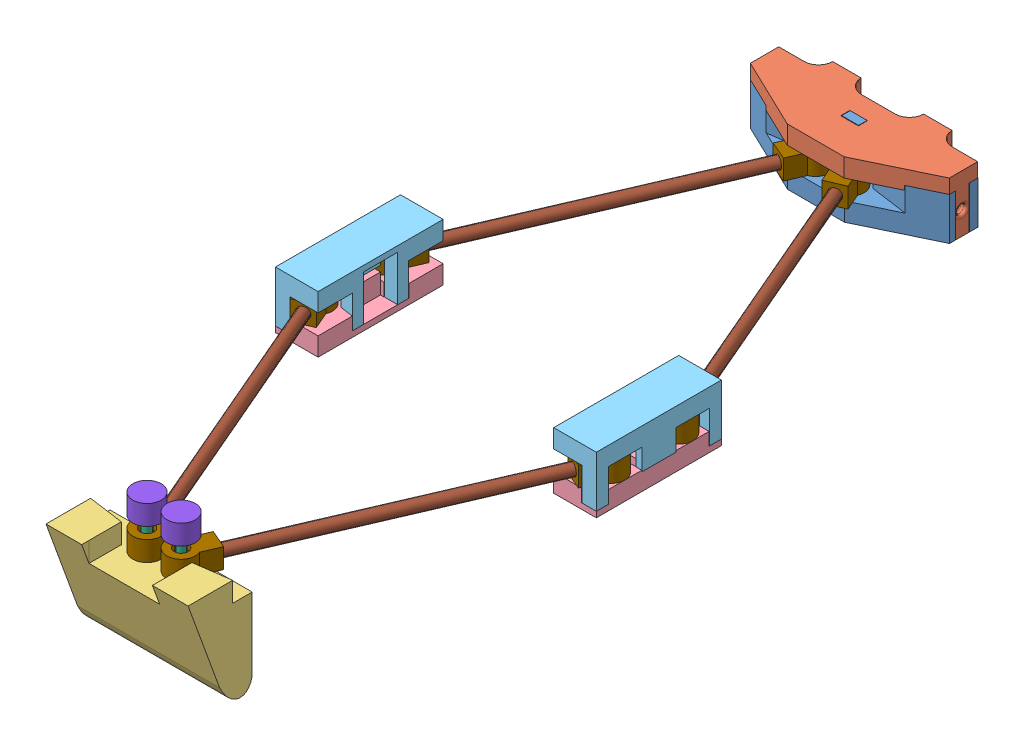
SolidWorks assembly rear_assembly, configuration Default. Lengths in mm.
Overall size (116.04 48.6 272.82).
37 component instances, 11 part files, 88 mates.
Components (placement in the parent):
- Hips3-1: Hips3 [Default] at (9.7538 31.3061 68.3502) size (70 26 22)
- Hips3top-1: Hips3top [Default] at (29.7538 51.3061 68.4502) x (-1 0 0) z (0 0 1) size (70.01 25 27)
- Foot3-1: Foot3 [Default] at (-5.2462 37.8061 311.7254) x (0 0 -1) z (0 -1 0) size (22.55 50 37.6)
- KneeJointBottom-1: KneeJointBottom [Default] at (-21.6962 31.3061 158.0878) x (0 0 1) z (-1 0 0) size (44 9 15)
- KneeJointTop-1: KneeJointTop [Default] at (-21.6962 51.3061 202.0878) x (0 0 -1) z (-1 0 0) size (44 18 15)
- RodFootJoint-1: RodFootJoint [Default] at (13.7538 17.8061 297.7254) size (3 36 3)
- RodFootJoint-2: RodFootJoint [Default] at (25.7538 17.8061 297.7254) size (3 36 3)
- RodHipKneeJoint-1: RodHipKneeJoint [Default] at (-31.6962 33.3061 192.0878) size (3 16 3)
- RodHipKneeJoint-2: RodHipKneeJoint [Default] at (-31.6962 33.3061 168.0878) x (0.999944 0 -0.010618) z (0.010618 0 0.999944) size (3 16 3)
- RodHipKneeJoint-3: RodHipKneeJoint [Default] at (25.7538 33.3061 62.4502) size (3 16 3)
- RodHipKneeJoint-4: RodHipKneeJoint [Default] at (13.7538 33.3061 62.4502) size (3 16 3)
- FootEndConnector-3: FootEndConnector [Default] at (25.7538 48.8061 297.7254) x (0.269607 0 -0.96297) z (0 1 0) size (10 10 9)
- FootEndConnector-4: FootEndConnector [Default] at (13.7538 48.8061 297.7254) x (-0.093538 0 -0.995616) z (0 1 0) size (10 10 9)
- KneeJointTop-2: KneeJointTop [Default] at (61.2038 51.3061 158.0878) x (0 0 1) z (1 0 0) size (44 18 15)
- KneeJointBottom-2: KneeJointBottom [Default] at (61.2038 31.3061 202.0878) x (0 0 -1) z (1 0 0) size (44 9 15)
- RodHipKneeJoint-5: RodHipKneeJoint [Default] at (71.2038 33.3061 192.0878) x (0.987949 0 0.154781) z (-0.154781 0 0.987949) size (3 16 3)
- RodHipKneeJoint-6: RodHipKneeJoint [Default] at (71.2038 33.3061 168.0878) x (0.987949 0 0.154781) z (-0.154781 0 0.987949) size (3 16 3)
- LegConnector1-1: LegConnector1 [Default] at (13.7538 44.8061 62.4502) x (-0.918588 0 -0.395217) z (-0.395217 0 0.918588) size (10 7 15)
- bushing-1: bushing [Default] at (13.7538 38.7061 62.4502) x (0.837169 0 0.546944) z (0.546944 0 -0.837169) size (7.5 5 7.5)
- LegConnector1-2: LegConnector1 [Default] at (25.7538 44.8061 62.4502) x (-0.918588 0 0.395217) z (0.395217 0 0.918588) size (10 7 15)
- bushing-2: bushing [Default] at (25.7538 38.7061 62.4502) x (-0.837169 0 -0.546944) z (-0.546944 0 0.837169) size (7.5 5 7.5)
- LegConnector1-4: LegConnector1 [Default] at (-31.6962 44.8061 192.0878) x (-0.918588 0 0.395217) z (0.395217 0 0.918588) size (10 7 15)
- bushing-4: bushing [Default] at (-31.6962 38.7061 192.0878) x (-0.837169 0 -0.546944) z (-0.546944 0 0.837169) size (7.5 5 7.5)
- LegConnector1-5: LegConnector1 [Default] at (-31.6962 44.8061 168.0878) x (0.918588 0 0.395217) z (0.395217 0 -0.918588) size (10 7 15)
- bushing-5: bushing [Default] at (-31.6962 38.7061 168.0878) x (-0.837169 0 -0.546944) z (-0.546944 0 0.837169) size (7.5 5 7.5)
- LegCarbon-1: LegCarbon [Default] at (11.7777 41.3061 293.1324) x (-0.661738 -0.693573 0.284709) z (0.637107 -0.720387 -0.274112) size (4 105 4)
- LegCarbon-2: LegCarbon [Default] at (-29.7201 41.3061 163.4949) x (-0.61253 0.745221 -0.263538) z (-0.684551 -0.666818 -0.294524) size (4 105 4)
- LegConnector1-6: LegConnector1 [Default] at (13.7538 44.8061 297.7254) x (0.918588 0 -0.395217) z (-0.395217 0 -0.918588) size (10 7 15)
- bushing-6: bushing [Default] at (13.7538 38.7061 297.7254) x (-0.429251 0 -0.903185) z (-0.903185 0 0.429251) size (7.5 5 7.5)
- LegConnector1-8: LegConnector1 [Default] at (71.2038 44.8061 168.0878) x (0.918588 0 -0.395217) z (-0.395217 0 -0.918588) size (10 7 15)
- bushing-8: bushing [Default] at (71.2038 38.7061 168.0878) x (-0.429251 0 -0.903185) z (-0.903185 0 0.429251) size (7.5 5 7.5)
- bushing-9: bushing [Default] at (25.7538 38.7061 297.7254) x (-0.429251 0 -0.903185) z (-0.903185 0 0.429251) size (7.5 5 7.5)
- LegConnector1-9: LegConnector1 [Default] at (71.2038 44.8061 192.0878) x (-0.918588 0 -0.395217) z (-0.395217 0 0.918588) size (10 7 15)
- bushing-10: bushing [Default] at (71.2038 38.7061 192.0878) x (-0.429251 0 -0.903185) z (-0.903185 0 0.429251) size (7.5 5 7.5)
- LegConnector1-10: LegConnector1 [Default] at (25.7538 44.8061 297.7254) x (0.918588 0 0.395217) z (0.395217 0 -0.918588) size (10 7 15)
- LegCarbon-3: LegCarbon [Default] at (27.7299 41.3061 67.0432) x (0.650562 -0.705991 -0.279901) z (-0.648515 -0.70822 0.27902) size (4 105 4)
- LegCarbon-4: LegCarbon [Default] at (27.7299 41.3061 293.1324) x (-0.617739 0.740108 -0.265779) z (-0.679854 -0.672488 -0.292504) size (4 105 4)
Mates (geometry in assembly coordinates):
- Coincident1: coincident anti-aligned: plane of Hips3-1 through (-15.2462 29.3061 54.3502) normal (0 0 -1); plane of Hips3top-1 through (-15.2462 31.3061 54.3502) normal (0 0 1)
- Coincident2: coincident aligned: plane of Hips3-1 through (9.7538 31.3061 68.3502) normal (0 -1 0); plane of Hips3top-1 through (29.7538 31.3061 68.4502) normal (0 -1 0)
- Coincident3: coincident aligned: plane of Hips3-1 through (-15.2462 36.3061 56.3502) normal (-1 0 0); plane of Hips3top-1 through (-15.2462 46.3061 46.4502) normal (-1 0 0)
- Coincident4: coincident anti-aligned: plane of KneeJointBottom-1 through (-21.6962 33.3061 158.0878) normal (0 1 0); plane of KneeJointTop-1 through (-21.6962 33.3061 202.0878) normal (0 -1 0)
- Coincident5: coincident aligned: plane of KneeJointBottom-1 through (-36.6962 36.3061 158.0878) normal (-1 0 0); plane of KneeJointTop-1 through (-36.6962 46.3061 202.0878) normal (-1 0 0)
- Coincident6: coincident aligned: plane of KneeJointBottom-1 through (-21.6962 36.3061 202.0878) normal (0 0 1); plane of KneeJointTop-1 through (-21.6962 46.3061 202.0878) normal (0 0 1)
- Coincident7: coincident aligned: plane of Hips3top-1 through (29.7538 51.3061 68.4502) normal (0 1 0); plane of KneeJointTop-1 through (-21.6962 51.3061 202.0878) normal (0 1 0)
- Coincident8: coincident anti-aligned: plane of Foot3-1 through (13.7538 17.8061 297.7254) normal (0 1 0); plane of RodFootJoint-1 through (13.7538 17.8061 297.7254) normal (0 -1 0)
- Concentric1: concentric anti-aligned: cylinder of Foot3-1 through (13.7538 17.8061 297.7254) axis (0 1 0) radius 1.6; cylinder of RodFootJoint-1 through (13.7538 53.8061 297.7254) axis (0 -1 0) radius 1.5
- Coincident9: coincident anti-aligned: plane of Foot3-1 through (25.7538 17.8061 297.7254) normal (0 1 0); plane of RodFootJoint-2 through (25.7538 17.8061 297.7254) normal (0 -1 0)
- Concentric2: concentric anti-aligned: cylinder of Foot3-1 through (25.7538 17.8061 297.7254) axis (0 1 0) radius 1.6; cylinder of RodFootJoint-2 through (25.7538 53.8061 297.7254) axis (0 -1 0) radius 1.5
- Parallel3: parallel anti-aligned: plane of Hips3-1 through (9.7538 36.3061 68.3502) normal (0 0 1); plane of Foot3-1 through (44.7538 37.8061 291.7254) normal (0 0 -1)
- Concentric3: concentric anti-aligned: cylinder of KneeJointBottom-1 through (-31.6962 33.3061 168.0878) axis (0 1 0) radius 1.55; cylinder of RodHipKneeJoint-2 through (-31.6962 49.3061 168.0878) axis (0 -1 0) radius 1.5
- Coincident11: coincident anti-aligned: plane of KneeJointTop-1 through (-31.6962 49.3061 168.0878) normal (0 -1 0); plane of RodHipKneeJoint-2 through (-31.6962 49.3061 168.0878) normal (0 1 0)
- Coincident12: coincident anti-aligned: plane of KneeJointTop-1 through (-31.6962 49.3061 192.0878) normal (0 -1 0); plane of RodHipKneeJoint-1 through (-31.6962 49.3061 192.0878) normal (0 1 0)
- Coincident13: coincident aligned: plane of RodHipKneeJoint-3 through (25.7538 49.3061 62.4502) normal (0 1 0); plane of RodHipKneeJoint-4 through (13.7538 49.3061 62.4502) normal (0 1 0)
- Coincident14: coincident anti-aligned: plane of Hips3top-1 through (13.7538 49.3061 62.4502) normal (0 -1 0); plane of RodHipKneeJoint-4 through (13.7538 49.3061 62.4502) normal (0 1 0)
- Concentric4: concentric aligned: cylinder of Hips3top-1 through (13.7538 49.3061 62.4502) axis (0 -1 0) radius 1.575; cylinder of RodHipKneeJoint-4 through (13.7538 49.3061 62.4502) axis (0 -1 0) radius 1.5
- Concentric5: concentric aligned: cylinder of Hips3top-1 through (25.7538 49.3061 62.4502) axis (0 -1 0) radius 1.575; cylinder of RodHipKneeJoint-3 through (25.7538 49.3061 62.4502) axis (0 -1 0) radius 1.5
- Concentric6: concentric aligned: cylinder of KneeJointTop-1 through (-31.6962 49.3061 192.0878) axis (0 -1 0) radius 1.55; cylinder of RodHipKneeJoint-1 through (-31.6962 49.3061 192.0878) axis (0 -1 0) radius 1.5
- Concentric7: concentric aligned: cylinder of RodFootJoint-1 through (45.7766 52.3061 157.2122) axis (0 -1 0) radius 1.5; cylinder of ? through (45.7766 18.4636 157.2122) axis (0 -1 0) radius 1.55
- Coincident15: coincident anti-aligned: plane of RodFootJoint-1 through (13.7538 53.8061 297.7254) normal (0 1 0); plane of FootEndConnector-4 through (13.7538 53.8061 297.7254) normal (0 -1 0)
- Concentric8: concentric aligned: cylinder of RodFootJoint-1 through (13.7538 53.8061 297.7254) axis (0 -1 0) radius 1.5; cylinder of FootEndConnector-4 through (13.7538 48.8061 297.7254) axis (0 -1 0) radius 1.55
- Coincident16: coincident anti-aligned: plane of RodFootJoint-2 through (25.7538 53.8061 297.7254) normal (0 1 0); plane of FootEndConnector-3 through (25.7538 53.8061 297.7254) normal (0 -1 0)
- Concentric9: concentric aligned: cylinder of RodFootJoint-2 through (25.7538 53.8061 297.7254) axis (0 -1 0) radius 1.5; cylinder of FootEndConnector-3 through (25.7538 48.8061 297.7254) axis (0 -1 0) radius 1.55
- Coincident17: coincident aligned: plane of RodHipKneeJoint-5 through (71.2038 49.3061 192.0878) normal (0 1 0); plane of RodHipKneeJoint-6 through (71.2038 49.3061 168.0878) normal (0 1 0)
- Coincident18: coincident anti-aligned: plane of KneeJointTop-2 through (71.2038 49.3061 192.0878) normal (0 -1 0); plane of RodHipKneeJoint-5 through (71.2038 49.3061 192.0878) normal (0 1 0)
- Concentric10: concentric aligned: cylinder of KneeJointTop-2 through (71.2038 49.3061 192.0878) axis (0 -1 0) radius 1.55; cylinder of RodHipKneeJoint-5 through (71.2038 49.3061 192.0878) axis (0 -1 0) radius 1.5
- Concentric11: concentric aligned: cylinder of KneeJointTop-2 through (71.2038 49.3061 168.0878) axis (0 -1 0) radius 1.55; cylinder of RodHipKneeJoint-6 through (71.2038 49.3061 168.0878) axis (0 -1 0) radius 1.5
- Coincident19: coincident anti-aligned: plane of KneeJointTop-2 through (61.2038 33.3061 158.0878) normal (0 -1 0); plane of KneeJointBottom-2 through (61.2038 33.3061 202.0878) normal (0 1 0)
- Coincident20: coincident aligned: plane of KneeJointTop-2 through (61.2038 46.3061 158.0878) normal (0 0 -1); plane of KneeJointBottom-2 through (61.2038 36.3061 158.0878) normal (0 0 -1)
- Coincident21: coincident aligned: plane of KneeJointTop-2 through (76.2038 46.3061 158.0878) normal (1 0 0); plane of KneeJointBottom-2 through (76.2038 36.3061 202.0878) normal (1 0 0)
- Coincident23: coincident aligned: plane of KneeJointTop-1 through (-21.6962 51.3061 202.0878) normal (0 1 0); plane of KneeJointTop-2 through (61.2038 51.3061 158.0878) normal (0 1 0)
- Coincident24: coincident anti-aligned: plane of LegConnector1-1 through (13.7538 38.7061 62.4502) normal (0 -1 0); plane of bushing-1 through (13.7538 38.7061 62.4502) normal (0 1 0)
- Concentric12: concentric anti-aligned: cylinder of LegConnector1-1 through (13.7538 37.8061 62.4502) axis (0 1 0) radius 2.425; cylinder of bushing-1 through (13.7538 42.9561 62.4502) axis (0 -1 0) radius 2.25
- Coincident25: coincident anti-aligned: plane of LegConnector1-2 through (25.7538 38.7061 62.4502) normal (0 -1 0); plane of bushing-2 through (25.7538 38.7061 62.4502) normal (0 1 0)
- Concentric13: concentric anti-aligned: cylinder of LegConnector1-2 through (25.7538 37.8061 62.4502) axis (0 1 0) radius 2.425; cylinder of bushing-2 through (25.7538 42.9561 62.4502) axis (0 -1 0) radius 2.25
- Concentric15: concentric anti-aligned: cylinder of RodHipKneeJoint-3 through (25.7538 49.3061 62.4502) axis (0 -1 0) radius 1.5; cylinder of bushing-2 through (25.7538 37.9561 62.4502) axis (0 1 0) radius 1.5
- Coincident27: coincident aligned: plane of LegConnector1-1 through (13.7538 44.8061 62.4502) normal (0 1 0); plane of LegConnector1-2 through (25.7538 44.8061 62.4502) normal (0 1 0)
- Concentric16: concentric anti-aligned: cylinder of RodHipKneeJoint-4 through (13.7538 49.3061 62.4502) axis (0 -1 0) radius 1.5; cylinder of bushing-1 through (13.7538 37.9561 62.4502) axis (0 1 0) radius 1.5
- Coincident28: coincident anti-aligned: plane of LegConnector1-4 through (-31.6962 38.7061 192.0878) normal (0 -1 0); plane of bushing-4 through (-31.6962 38.7061 192.0878) normal (0 1 0)
- Concentric17: concentric anti-aligned: cylinder of LegConnector1-4 through (-31.6962 37.8061 192.0878) axis (0 1 0) radius 2.425; cylinder of bushing-4 through (-31.6962 42.9561 192.0878) axis (0 -1 0) radius 2.25
- Concentric18: concentric anti-aligned: cylinder of LegConnector1-5 through (-31.6962 37.8061 168.0878) axis (0 1 0) radius 2.425; cylinder of bushing-5 through (-31.6962 42.9561 168.0878) axis (0 -1 0) radius 2.25
- Coincident29: coincident anti-aligned: plane of LegConnector1-5 through (-31.6962 38.7061 168.0878) normal (0 -1 0); plane of bushing-5 through (-31.6962 38.7061 168.0878) normal (0 1 0)
- Concentric19: concentric anti-aligned: cylinder of RodHipKneeJoint-2 through (-31.6962 49.3061 168.0878) axis (0 -1 0) radius 1.5; cylinder of bushing-5 through (-31.6962 37.9561 168.0878) axis (0 1 0) radius 1.5
- Concentric20: concentric anti-aligned: cylinder of RodHipKneeJoint-1 through (-31.6962 49.3061 192.0878) axis (0 -1 0) radius 1.5; cylinder of bushing-4 through (-31.6962 37.9561 192.0878) axis (0 1 0) radius 1.5
- Concentric21: concentric anti-aligned: cylinder of LegConnector1-1 through (9.8016 41.3061 71.6361) axis (0.395217 0 -0.918588) radius 2.075; cylinder of LegCarbon-2 through (11.7777 41.3061 67.0432) axis (-0.395217 0 0.918588) radius 2
- Coincident32: coincident anti-aligned: plane of LegConnector1-1 through (11.7777 44.8061 67.0432) normal (-0.395217 0 0.918588); plane of LegCarbon-2 through (11.7777 41.3061 67.0432) normal (0.395217 0 -0.918588)
- Coincident33: coincident anti-aligned: plane of LegConnector1-5 through (-29.7201 44.8061 163.4949) normal (0.395217 0 -0.918588); plane of LegCarbon-2 through (-29.7201 41.3061 163.4949) normal (-0.395217 0 0.918588)
- Concentric22: concentric aligned: cylinder of LegConnector1-5 through (-27.744 41.3061 158.9019) axis (-0.395217 0 0.918588) radius 2.075; cylinder of LegCarbon-2 through (11.7777 41.3061 67.0432) axis (-0.395217 0 0.918588) radius 2
- Concentric23: concentric anti-aligned: cylinder of LegConnector1-4 through (-27.744 41.3061 201.2737) axis (-0.395217 0 -0.918588) radius 2.075; cylinder of LegCarbon-1 through (-29.7201 41.3061 196.6807) axis (0.395217 0 0.918588) radius 2
- Coincident34: coincident anti-aligned: plane of LegConnector1-4 through (-29.7201 44.8061 196.6807) normal (0.395217 0 0.918588); plane of LegCarbon-1 through (-29.7201 41.3061 196.6807) normal (-0.395217 0 -0.918588)
- Coincident35: coincident anti-aligned: plane of LegConnector1-6 through (13.7538 38.7061 297.7254) normal (0 -1 0); plane of bushing-6 through (13.7538 38.7061 297.7254) normal (0 1 0)
- Concentric24: concentric anti-aligned: cylinder of LegConnector1-6 through (13.7538 37.8061 297.7254) axis (0 1 0) radius 2.425; cylinder of bushing-6 through (13.7538 42.9561 297.7254) axis (0 -1 0) radius 2.25
- Concentric25: concentric anti-aligned: cylinder of RodFootJoint-1 through (13.7538 53.8061 297.7254) axis (0 -1 0) radius 1.5; cylinder of bushing-6 through (13.7538 37.9561 297.7254) axis (0 1 0) radius 1.5
- Concentric27: concentric aligned: cylinder of LegCarbon-1 through (-29.7201 41.3061 196.6807) axis (0.395217 0 0.918588) radius 2; cylinder of LegConnector1-6 through (9.8016 41.3061 288.5395) axis (0.395217 0 0.918588) radius 2.075
- Coincident37: coincident anti-aligned: plane of LegCarbon-1 through (11.7777 41.3061 293.1324) normal (0.395217 0 0.918588); plane of LegConnector1-6 through (11.7777 44.8061 293.1324) normal (-0.395217 0 -0.918588)
- Concentric28: concentric anti-aligned: cylinder of LegConnector1-8 through (71.2038 37.8061 168.0878) axis (0 1 0) radius 2.425; cylinder of bushing-8 through (71.2038 42.9561 168.0878) axis (0 -1 0) radius 2.25
- Coincident38: coincident anti-aligned: plane of LegConnector1-8 through (71.2038 38.7061 168.0878) normal (0 -1 0); plane of bushing-8 through (71.2038 38.7061 168.0878) normal (0 1 0)
- Coincident39: coincident anti-aligned: plane of LegConnector1-9 through (71.2038 38.7061 192.0878) normal (0 -1 0); plane of bushing-10 through (71.2038 38.7061 192.0878) normal (0 1 0)
- Coincident40: coincident anti-aligned: plane of bushing-9 through (25.7538 38.7061 297.7254) normal (0 1 0); plane of LegConnector1-10 through (25.7538 38.7061 297.7254) normal (0 -1 0)
- Concentric29: concentric anti-aligned: cylinder of bushing-9 through (25.7538 42.9561 297.7254) axis (0 -1 0) radius 2.25; cylinder of LegConnector1-10 through (25.7538 37.8061 297.7254) axis (0 1 0) radius 2.425
- Concentric30: concentric anti-aligned: cylinder of LegConnector1-9 through (71.2038 37.8061 192.0878) axis (0 1 0) radius 2.425; cylinder of bushing-10 through (71.2038 42.9561 192.0878) axis (0 -1 0) radius 2.25
- Concentric31: concentric anti-aligned: cylinder of ? through (-83.3882 75.6271 105.84) axis (-0.378796 -0.893988 -0.239372) radius 2.25; cylinder of ? through (-85.339 71.0231 104.6072) axis (0.378796 0.893988 0.239372) radius 2.425
- Coincident41: coincident anti-aligned: plane of ? through (-84.9981 71.8277 104.8227) normal (0.378796 0.893988 0.239372); plane of ? through (-84.9981 71.8277 104.8227) normal (-0.378796 -0.893988 -0.239372)
- Concentric33: concentric anti-aligned: cylinder of RodFootJoint-2 through (25.7538 53.8061 297.7254) axis (0 -1 0) radius 1.5; cylinder of bushing-9 through (25.7538 37.9561 297.7254) axis (0 1 0) radius 1.5
- Coincident43: coincident aligned: plane of bushing-8 through (71.2038 37.9561 168.0878) normal (0 -1 0); plane of bushing-10 through (71.2038 37.9561 192.0878) normal (0 -1 0)
- Concentric34: concentric anti-aligned: cylinder of RodHipKneeJoint-6 through (71.2038 49.3061 168.0878) axis (0 -1 0) radius 1.5; cylinder of bushing-8 through (71.2038 37.9561 168.0878) axis (0 1 0) radius 1.5
- Concentric35: concentric anti-aligned: cylinder of RodHipKneeJoint-5 through (71.2038 49.3061 192.0878) axis (0 -1 0) radius 1.5; cylinder of bushing-10 through (71.2038 37.9561 192.0878) axis (0 1 0) radius 1.5
- Coincident45: coincident anti-aligned: plane of LegConnector1-2 through (27.7299 44.8061 67.0432) normal (0.395217 0 0.918588); plane of LegCarbon-3 through (27.7299 41.3061 67.0432) normal (-0.395217 0 -0.918588)
- Concentric36: concentric aligned: cylinder of LegConnector1-2 through (29.706 41.3061 71.6361) axis (-0.395217 0 -0.918588) radius 2.075; cylinder of LegCarbon-3 through (69.2277 41.3061 163.4949) axis (-0.395217 0 -0.918588) radius 2
- Coincident46: coincident anti-aligned: plane of LegConnector1-8 through (69.2277 44.8061 163.4949) normal (-0.395217 0 -0.918588); plane of LegCarbon-3 through (69.2277 41.3061 163.4949) normal (0.395217 0 0.918588)
- Concentric37: concentric anti-aligned: cylinder of LegConnector1-8 through (67.2516 41.3061 158.9019) axis (0.395217 0 0.918588) radius 2.075; cylinder of LegCarbon-3 through (69.2277 41.3061 163.4949) axis (-0.395217 0 -0.918588) radius 2
- Perpendicular2: perpendicular: plane of Hips3top-1 through (29.7538 46.3061 68.4502) normal (0 0 1); plane of KneeJointTop-1 through (-21.6962 46.3061 202.0878) normal (1 0 0)
- Coincident47: coincident anti-aligned: plane of LegConnector1-9 through (69.2277 44.8061 196.6807) normal (-0.395217 0 0.918588); plane of LegCarbon-4 through (69.2277 41.3061 196.6807) normal (0.395217 0 -0.918588)
- Concentric38: concentric anti-aligned: cylinder of LegConnector1-9 through (67.2516 41.3061 201.2737) axis (0.395217 0 -0.918588) radius 2.075; cylinder of LegCarbon-4 through (69.2277 41.3061 196.6807) axis (-0.395217 0 0.918588) radius 2
- Coincident48: coincident anti-aligned: plane of LegConnector1-10 through (27.7299 44.8061 293.1324) normal (0.395217 0 -0.918588); plane of LegCarbon-4 through (27.7299 41.3061 293.1324) normal (-0.395217 0 0.918588)
- Concentric39: concentric aligned: cylinder of LegConnector1-10 through (29.706 41.3061 288.5395) axis (-0.395217 0 0.918588) radius 2.075; cylinder of LegCarbon-4 through (69.2277 41.3061 196.6807) axis (-0.395217 0 0.918588) radius 2
- Coincident49: coincident aligned: plane of KneeJointTop-1 through (-21.6962 46.3061 158.0878) normal (0 0 -1); plane of KneeJointTop-2 through (61.2038 46.3061 158.0878) normal (0 0 -1)
- LimitDistance1: limit distance = 99.8 mm: cylinder of KneeJointTop-1 through (-31.6962 45.3061 180.0878) axis (0 -1 0) radius 1.55; cylinder of KneeJointTop-2 through (71.2038 45.3061 180.0878) axis (0 -1 0) radius 1.55
- Coincident50: coincident anti-aligned: plane of Foot3-1 through (44.7538 37.8061 311.7254) normal (0 1 0); plane of LegConnector1-10 through (25.7538 37.8061 297.7254) normal (0 -1 0)
- Coincident51: coincident anti-aligned: plane of Foot3-1 through (44.7538 37.8061 311.7254) normal (0 1 0); plane of LegConnector1-6 through (13.7538 37.8061 297.7254) normal (0 -1 0)
- Coincident52: coincident anti-aligned: plane of KneeJointBottom-1 through (-21.6962 37.8061 158.0878) normal (0 1 0); plane of LegConnector1-4 through (-31.6962 37.8061 192.0878) normal (0 -1 0)
- Coincident53: coincident anti-aligned: plane of KneeJointBottom-1 through (-21.6962 37.8061 158.0878) normal (0 1 0); plane of LegConnector1-5 through (-31.6962 37.8061 168.0878) normal (0 -1 0)
- Coincident54: coincident anti-aligned: plane of KneeJointBottom-2 through (61.2038 37.8061 202.0878) normal (0 1 0); plane of LegConnector1-8 through (71.2038 37.8061 168.0878) normal (0 -1 0)
- Coincident55: coincident anti-aligned: plane of KneeJointBottom-2 through (61.2038 37.8061 202.0878) normal (0 1 0); plane of LegConnector1-9 through (71.2038 37.8061 192.0878) normal (0 -1 0)
- Coincident56: coincident anti-aligned: plane of Hips3-1 through (13.7538 37.8061 62.3502) normal (0 1 0); plane of LegConnector1-1 through (13.7538 37.8061 62.4502) normal (0 -1 0)
- Coincident57: coincident anti-aligned: plane of Hips3-1 through (13.7538 37.8061 62.3502) normal (0 1 0); plane of LegConnector1-2 through (25.7538 37.8061 62.4502) normal (0 -1 0)
